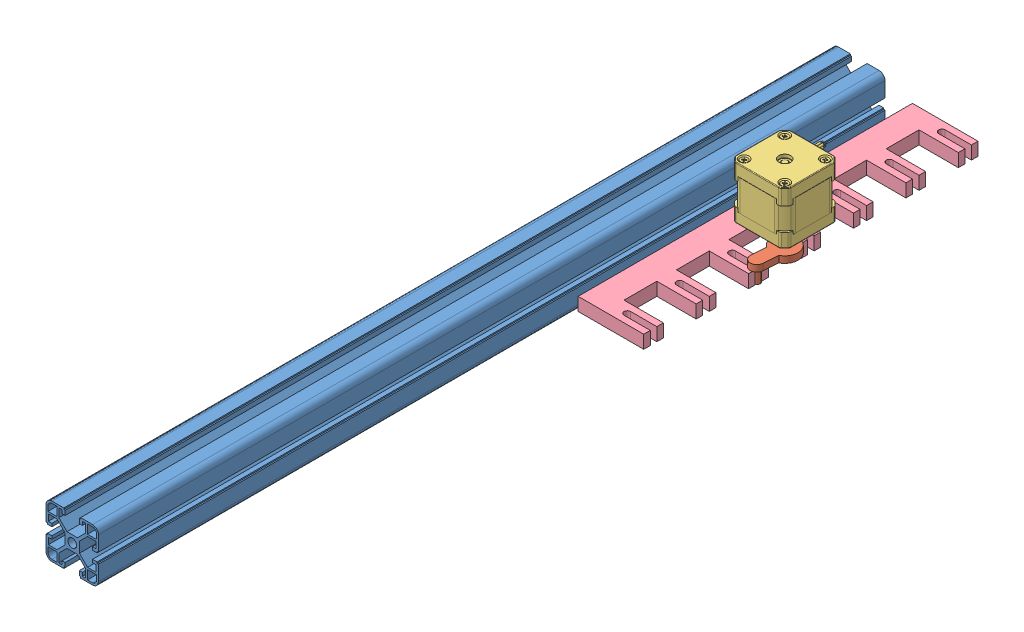
SolidWorks assembly geneva_test, configuration Default. Lengths in mm.
Overall size (111.15 72 620.96).
4 component instances, 4 part files, 7 mates.
Components (placement in the parent):
- tray_backward_top_slider-1: tray_backward_top_slider [Default] at (170.8965 343.8143 167.6962) size (40 40 600)
- geneva_shaft-2: geneva_shaft [Default] at (240.8965 338.8143 294.1407) x (-0.067702 0 0.997706) z (0.997706 0 0.067702) size (35 15 20)
- nema  17-2: nema  17 [По умолчанию] at (240.8965 395.8143 294.1407) x (1 0 0) z (0 0 -1) size (42.3 62 51.35)
- geneva_slider2-1: geneva_slider2 [Default] at (240.8965 323.8143 396.7375) x (0 0 -1) z (1 0 0) size (255 10 50)
Mates (geometry in assembly coordinates):
- Concentric9: concentric aligned: cylinder of geneva_shaft-2 through (240.8965 333.8143 294.1407) axis (0 1 0) radius 2.5; cylinder of nema  17-2 through (240.8965 333.8143 294.1407) axis (0 1 0) radius 2.5
- Coincident9: coincident aligned: plane of geneva_shaft-2 through (240.8965 333.8143 294.1407) normal (0 -1 0); plane of nema  17-2 through (240.8965 333.8143 294.1407) normal (0 -1 0)
- Coincident12: coincident anti-aligned: plane of tray_backward_top_slider-1 through (190.8965 339.8487 767.6962) normal (1 0 0); plane of geneva_slider2-1 through (190.8965 333.8143 401.7375) normal (-1 0 0)
- Coincident13: coincident: line of tray_backward_top_slider-1 through (186.3965 323.8143 167.6962) axis (-1 0 0); plane of geneva_slider2-1 through (220.8965 323.8143 394.2375) normal (0 -1 0)
- Coincident14: coincident aligned: plane of tray_backward_top_slider-1 through (186.3965 323.8143 767.6962) normal (0 -1 0); plane of geneva_slider2-1 through (220.8965 323.8143 394.2375) normal (0 -1 0)
- Coincident15: coincident anti-aligned: plane of geneva_shaft-2 through (240.8965 333.8143 294.1407) normal (0 -1 0); plane of geneva_slider2-1 through (220.8965 333.8143 394.2375) normal (0 1 0)
- Tangent3: tangent anti-aligned: cylinder of geneva_shaft-2 through (238.0032 323.8143 313.9303) axis (0 1 0) radius 2.5; plane of geneva_slider2-1 through (220.8965 333.8143 311.4303) normal (0 0 1)
